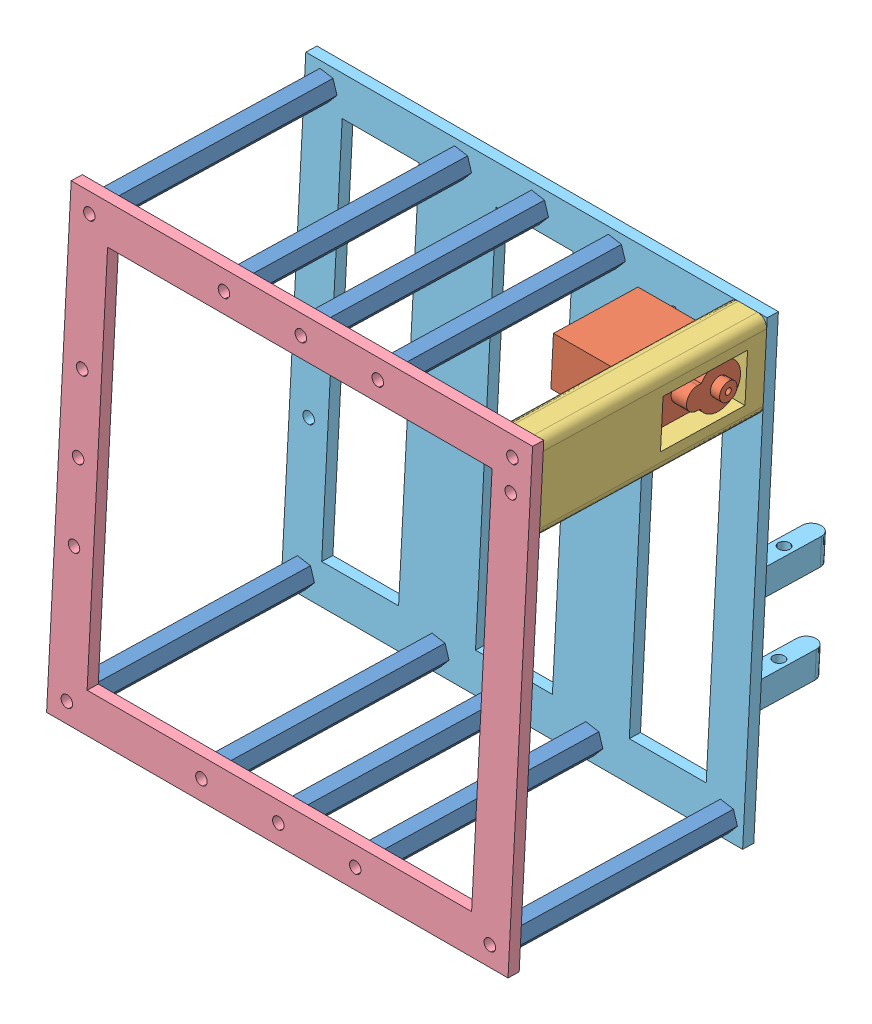
SolidWorks assembly Caixa, configuration Valor predeterminado. Lengths in mm.
Overall size (123.28 125.05 92.67).
13 component instances, 5 part files, 47 mates.
Components (placement in the parent):
- Standoff-Garra-1: Standoff-Garra [Valor predeterminado] at (-111.1644 51.3854 160.8703) x (0.999874 -0.000323 -0.015894) z (0.015894 0.040674 0.999046) size (6.82 6.52 60)
- Standoff-Garra-4: Standoff-Garra [Valor predeterminado] at (-2.6424 -60.0375 163.6801) x (0.999874 -0.000323 -0.015894) z (0.015894 0.040674 0.999046) size (6.82 6.52 60)
- Standoff-Garra-5: Standoff-Garra [Valor predeterminado] at (-112.6189 -58.513 165.3677) x (0.999874 -0.000323 -0.015894) z (0.015894 0.040674 0.999046) size (6.82 6.52 60)
- Servo-9g-1: Servo-9g [Predeterminado] at (-13.8129 37.8242 176.2392) x (0.013222 0.999076 -0.040886) z (0.999786 -0.01386 -0.015342) size (12.5 32.7 29.4)
- Suporte-Servo-Caixa-1: Suporte-Servo-Caixa [Valor predeterminado] at (14.6429 35.8761 174.7202) x (0.015894 0.040674 0.999046) z (-0.999786 0.01386 0.015342) size (60 22.5 10)
- Base-Caixa-2: Base-Caixa [Valor predeterminado] at (9.0925 44.0113 219.3146) x (-0.013222 -0.999076 0.040886) z (0.015894 0.040674 0.999046) size (120 120 3)
- Tampa-Caixa-2: Tampa-Caixa [Valor predeterminado] at (-100.6077 -63.9113 162.3935) x (0.013222 0.999076 -0.040886) z (0.015894 0.040674 0.999046) size (120 120 23)
- Standoff-Garra-6: Standoff-Garra [Valor predeterminado] at (-76.1719 50.9003 160.3333) x (0.999874 -0.000323 -0.015894) z (0.015894 0.040674 0.999046) size (6.82 6.52 60)
- Standoff-Garra-7: Standoff-Garra [Valor predeterminado] at (-36.1805 50.3459 159.7197) x (0.999874 -0.000323 -0.015894) z (0.015894 0.040674 0.999046) size (6.82 6.52 60)
- Standoff-Garra-8: Standoff-Garra [Valor predeterminado] at (-56.1762 50.6231 160.0265) x (0.999874 -0.000323 -0.015894) z (0.015894 0.040674 0.999046) size (6.82 6.52 60)
- Standoff-Garra-9: Standoff-Garra [Valor predeterminado] at (-37.6349 -59.5525 164.2171) x (0.999874 -0.000323 -0.015894) z (0.015894 0.040674 0.999046) size (6.82 6.52 60)
- Standoff-Garra-10: Standoff-Garra [Valor predeterminado] at (-57.6306 -59.2753 164.5239) x (0.999874 -0.000323 -0.015894) z (0.015894 0.040674 0.999046) size (6.82 6.52 60)
- Standoff-Garra-11: Standoff-Garra [Valor predeterminado] at (-77.6264 -58.9981 164.8308) x (0.999874 -0.000323 -0.015894) z (0.015894 0.040674 0.999046) size (6.82 6.52 60)
Mates (geometry in assembly coordinates):
- Concêntrico1: concentric anti-aligned: circle of ?; circle of Standoff-Garra-1
- Coincidente1: coincident anti-aligned: plane of ? through (-53.4731 59.0997 121.5) normal (0 0 1); plane of Standoff-Garra-1
- Concêntrico2: concentric anti-aligned: circle of ?; circle of ?
- Coincidente2: coincident anti-aligned: plane of ? through (-53.4731 59.0997 121.5) normal (0 0 1); plane of ? through (-65.692 -42.7688 121.5) normal (0 0 -1)
- Concêntrico3: concentric anti-aligned: circle of ?; circle of ?
- Coincidente3: coincident anti-aligned: plane of ? through (-53.4731 59.0997 121.5) normal (0 0 1); plane of ? through (67.663 60.3689 121.5) normal (0 0 -1)
- Concêntrico4: concentric anti-aligned: circle of ?; circle of Standoff-Garra-4
- Coincidente4: coincident anti-aligned: plane of ? through (-53.4731 59.0997 121.5) normal (0 0 1); plane of Standoff-Garra-4
- Concêntrico5: concentric anti-aligned: circle of ?; circle of ?
- Coincidente5: coincident anti-aligned: plane of ? through (-65.692 -42.7688 181.5) normal (0 0 1); plane of ? through (-53.4731 59.0997 181.5) normal (0 0 -1)
- Concêntrico6: concentric anti-aligned: circle of ?; circle of ?
- Concêntrico7: concentric aligned: circle of ?; circle of ?
- Coincidente6: coincident anti-aligned: plane of ? through (67.663 60.3689 181.5) normal (0 0 1); plane of ? through (-53.6538 58.919 181.5) normal (0 0 -1)
- Concêntrico8: concentric aligned: circle of Standoff-Garra-1; circle of ?
- Coincidente16: coincident anti-aligned: plane of Servo-9g-1 through (9.0844 43.288 164.2916) normal (0.013222 0.999076 -0.040886); plane of Suporte-Servo-Caixa-1 through (4.5854 43.3504 164.3607) normal (-0.013222 -0.999076 0.040886)
- Coincidente17: coincident anti-aligned: plane of Servo-9g-1 through (8.9192 30.7996 164.8027) normal (-0.015894 -0.040674 -0.999046); plane of Suporte-Servo-Caixa-1 through (4.5854 43.3504 164.3607) normal (0.015894 0.040674 0.999046)
- Concêntrico10: concentric aligned: circle of Standoff-Garra-4; circle of ?
- Coincidente20: coincident anti-aligned: plane of Servo-9g-1 through (4.9462 44.2737 187.039) normal (0.999786 -0.01386 -0.015342); plane of Suporte-Servo-Caixa-1 through (4.645 36.0147 174.8737) normal (-0.999786 0.01386 0.015342)
- Concêntrico11: concentric aligned: circle of ?; circle of Base-Caixa-2
- Concêntrico12: concentric aligned: circle of ?; circle of Base-Caixa-2
- Coincidente26: coincident anti-aligned: plane of Standoff-Garra-1; plane of ? through (-95.5957 66.0875 78.9576) normal (0 0 1)
- Coincidente27: coincident anti-aligned: plane of Standoff-Garra-1 through (-110.2108 53.8259 220.8131) normal (0.015894 0.040674 0.999046); plane of Base-Caixa-2 through (9.0925 44.0113 219.3146) normal (-0.015894 -0.040674 -0.999046)
- Concêntrico13: concentric anti-aligned: circle of Standoff-Garra-1; circle of Base-Caixa-2
- Concêntrico14: concentric aligned: circle of Standoff-Garra-4; circle of ?
- Coincidente30: coincident anti-aligned: plane of Standoff-Garra-4; plane of ? through (-95.5957 66.0875 78.9576) normal (0 0 1)
- Coincidente34: coincident anti-aligned: plane of Standoff-Garra-5 through (-111.6652 -56.0725 225.3105) normal (0.015894 0.040674 0.999046); plane of Base-Caixa-2 through (9.0925 44.0113 219.3146) normal (-0.015894 -0.040674 -0.999046)
- Concêntrico15: concentric anti-aligned: circle of Standoff-Garra-5; circle of Base-Caixa-2
- Coincidente41: coincident anti-aligned: plane of Suporte-Servo-Caixa-1 through (5.5257 50.5828 219.1038) normal (0.015894 0.040674 0.999046); plane of Base-Caixa-2 through (9.0925 44.0113 219.3146) normal (-0.015894 -0.040674 -0.999046)
- Coincidente45: coincident anti-aligned: plane of Suporte-Servo-Caixa-1 through (4.5721 48.1424 159.161) normal (-0.015894 -0.040674 -0.999046); plane of Tampa-Caixa-2 through (-100.56 -63.7893 165.3907) normal (0.015894 0.040674 0.999046)
- Coincidente46: coincident anti-aligned: plane of Standoff-Garra-4 through (-1.6887 -57.5971 223.6229) normal (0.015894 0.040674 0.999046); plane of Base-Caixa-2 through (9.0925 44.0113 219.3146) normal (-0.015894 -0.040674 -0.999046)
- Concêntrico16: concentric aligned: circle of Standoff-Garra-4; circle of Tampa-Caixa-2
- Concêntrico17: concentric anti-aligned: circle of Standoff-Garra-4; circle of Base-Caixa-2
- Concêntrico18: concentric aligned: circle of Standoff-Garra-5; circle of Tampa-Caixa-2
- Coincidente50: coincident aligned: plane of Suporte-Servo-Caixa-1 through (4.645 36.0147 174.8737) normal (-0.999786 0.01386 0.015342); plane of Tampa-Caixa-2 through (3.0699 -61.878 160.6613) normal (-0.999786 0.01386 0.015342)
- Coincidente51: coincident aligned: plane of Suporte-Servo-Caixa-1 through (4.5721 48.1424 159.161) normal (0.013222 0.999076 -0.040886); plane of Base-Caixa-2 through (15.5713 50.5663 221.9475) normal (0.013222 0.999076 -0.040886)
- Concêntrico19: concentric anti-aligned: circle of Tampa-Caixa-2; circle of Standoff-Garra-6
- Coincidente53: coincident anti-aligned: plane of Tampa-Caixa-2 through (-100.56 -63.7893 165.3907) normal (0.015894 0.040674 0.999046); plane of Standoff-Garra-6 through (-76.1719 50.9003 160.3333) normal (-0.015894 -0.040674 -0.999046)
- Concêntrico20: concentric aligned: circle of Tampa-Caixa-2; circle of Standoff-Garra-8
- Coincidente55: coincident anti-aligned: plane of Tampa-Caixa-2 through (-100.56 -63.7893 165.3907) normal (0.015894 0.040674 0.999046); plane of Standoff-Garra-8 through (-56.1762 50.6231 160.0265) normal (-0.015894 -0.040674 -0.999046)
- Concêntrico21: concentric aligned: circle of Tampa-Caixa-2; circle of Standoff-Garra-7
- Coincidente57: coincident anti-aligned: plane of Tampa-Caixa-2 through (-100.56 -63.7893 165.3907) normal (0.015894 0.040674 0.999046); plane of Standoff-Garra-7 through (-36.1805 50.3459 159.7197) normal (-0.015894 -0.040674 -0.999046)
- Concêntrico22: concentric aligned: circle of Tampa-Caixa-2; circle of Standoff-Garra-9
- Coincidente59: coincident anti-aligned: plane of Tampa-Caixa-2 through (-100.56 -63.7893 165.3907) normal (0.015894 0.040674 0.999046); plane of Standoff-Garra-9 through (-37.6349 -59.5525 164.2171) normal (-0.015894 -0.040674 -0.999046)
- Concêntrico23: concentric aligned: circle of Tampa-Caixa-2; circle of Standoff-Garra-10
- Coincidente61: coincident anti-aligned: plane of Tampa-Caixa-2 through (-100.56 -63.7893 165.3907) normal (0.015894 0.040674 0.999046); plane of Standoff-Garra-10 through (-57.6306 -59.2753 164.5239) normal (-0.015894 -0.040674 -0.999046)
- Concêntrico24: concentric aligned: circle of Tampa-Caixa-2; circle of Standoff-Garra-11
- Coincidente63: coincident anti-aligned: plane of Tampa-Caixa-2 through (-100.56 -63.7893 165.3907) normal (0.015894 0.040674 0.999046); plane of Standoff-Garra-11 through (-77.6264 -58.9981 164.8308) normal (-0.015894 -0.040674 -0.999046)
